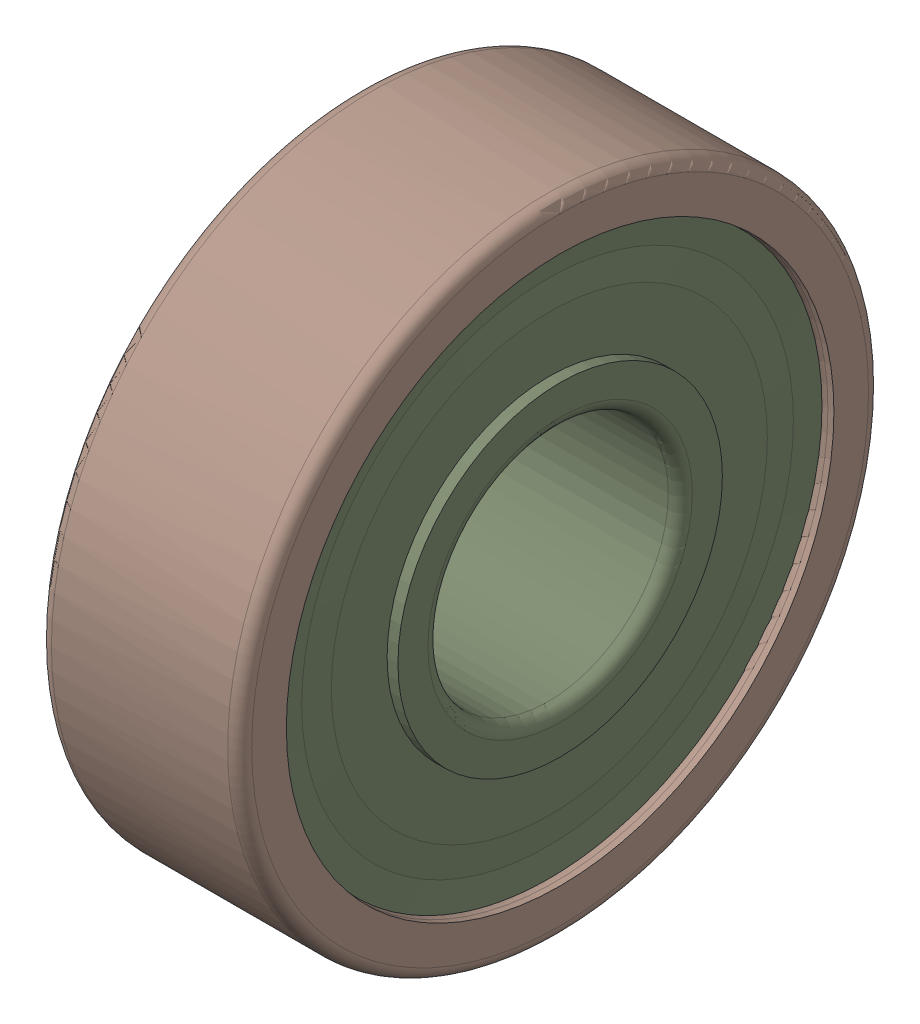
SolidWorks assembly SKF_6201-2RSL, configuration Default. Lengths in mm.
Overall size (10 32 32).
9 component instances, 3 part files, 0 mates.
Components (placement in the parent):
- SKF_6201-2RSL_ball1-1: SKF_6201-2RSL_ball1 [Default] at (10 17.8584 -8.6001) x (-1 0 0) z (0 0 1) size (6 6 6)
- SKF_6201-2RSL_ball1-2: SKF_6201-2RSL_ball1 [Default] at (10 8.5523 -10.7242) x (-1 0 0) z (0 0 1) size (6 6 6)
- SKF_6201-2RSL_ball1-3: SKF_6201-2RSL_ball1 [Default] at (10 1.0893 -4.7727) x (-1 0 0) z (0 0 1) size (6 6 6)
- SKF_6201-2RSL_ball1-4: SKF_6201-2RSL_ball1 [Default] at (10 1.0893 4.7727) x (-1 0 0) z (0 0 1) size (6 6 6)
- SKF_6201-2RSL_ball1-5: SKF_6201-2RSL_ball1 [Default] at (10 8.5523 10.7242) x (-1 0 0) z (0 0 1) size (6 6 6)
- SKF_6201-2RSL_ball1-6: SKF_6201-2RSL_ball1 [Default] at (10 17.8584 8.6001) x (-1 0 0) z (0 0 1) size (6 6 6)
- SKF_6201-2RSL_ball1-7: SKF_6201-2RSL_ball1 [Default] at (10 22 0) x (-1 0 0) z (0 0 1) size (6 6 6)
- SKF_6201-2RSL_or-1: SKF_6201-2RSL_or [Default] x (1 0 0) z (0 0 -1) size (10 32 32)
- SKF_6201-2RSL_ir-1: SKF_6201-2RSL_ir [Default] x (1 0 0) z (0 0 -1) size (10 27.34 27.34)
